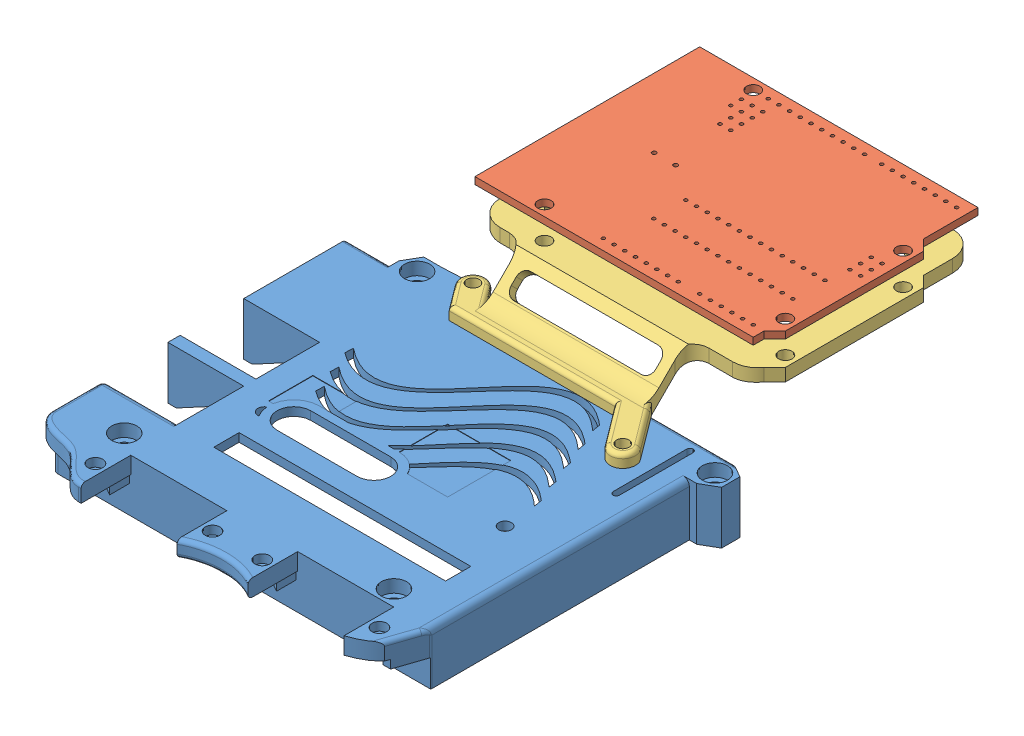
SolidWorks assembly assembly_bottom_2, configuration По умолчанию. Lengths in mm.
Overall size (96.45 30.98 145.71).
3 component instances, 3 part files, 9 mates.
Components (placement in the parent):
- top-1: top [По умолчанию] at (-39.8062 31.8791 -9.7446) size (96.45 12.67 88.75)
- unoboard blue-1: unoboard blue [Default] at (-18.9586 62.8594 -19.3652) x (0 0 1) z (-1 0 0) size (53.34 1.65 68.58)
- UNO_stand-1: UNO_stand [По умолчанию] at (-39.8062 44.3791 -9.7446) x (1 0 0) z (0 1 0) size (68.58 78.2 11)
Mates (geometry in assembly coordinates):
- На месте1: in place: plane of ? through (0 36.9 0) normal (0 1 0); plane of ? through (0 36.9 0) normal (0 1 0); moOrthogonalPlaneRef_w of ? through (0 36.9 0) normal (0 1 0); plane of ? through (0 36.9 0) normal (0 0 -1); plane of ? through (0 36.9 0) normal (0 1 0); line of ? through (-50 0 36.9) axis (0 1 0); plane of top-1 through (-39.8062 44.3791 -9.7446) normal (0 1 0); unknown of UNO_stand-1
- Совпадение1: coincident aligned: plane of top-1; plane of UNO_stand-1
- Совпадение2: coincident aligned: moOrthogonalPlaneRef_w of top-1 through (-39.8062 44.3791 -9.7446) normal (0 0 -1); plane of UNO_stand-1 through (-39.8062 44.3791 -9.7446) normal (0 0 -1)
- Совпадение3: coincident anti-aligned: moOrthogonalPlaneRef_w of top-1 through (-39.8062 44.3791 -9.7446) normal (-1 0 0); plane of UNO_stand-1 through (-39.8062 44.3791 -9.7446) normal (1 0 0)
- Параллельность1: parallel aligned: plane of top-1 through (-39.8062 44.3791 -9.7446) normal (0 1 0); plane of assembly through (0 0 0) normal (0 1 0)
- Параллельность2: parallel aligned: plane of top-1 through (50.1938 44.3791 -9.7446) normal (1 0 0); plane of assembly through (0 0 0) normal (1 0 0)
- Параллельность4: parallel aligned: plane of top-1 through (-39.8062 44.3791 60.2554) normal (0 0 1); plane of assembly through (0 0 0) normal (0 0 1)
- Концентричный1: concentric aligned: cylinder of unoboard blue-1 through (47.0814 61.2094 -26.9852) axis (0 1 0) radius 1.5875; cylinder of UNO_stand-1 through (47.0814 52.3791 -26.9852) axis (0 1 0) radius 1.5875
- Концентричный2: concentric aligned: cylinder of unoboard blue-1 through (-3.7186 61.2094 -70.1652) axis (0 1 0) radius 1.5875; cylinder of UNO_stand-1 through (-3.7186 52.3791 -70.1652) axis (0 1 0) radius 1.5875
